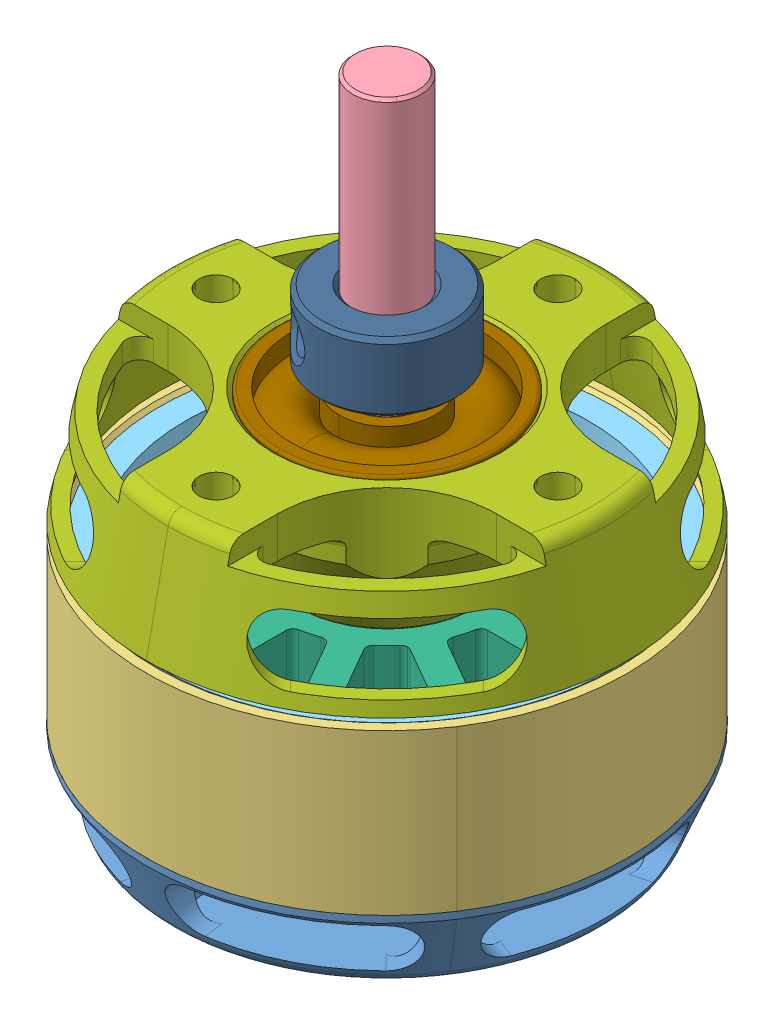
SolidWorks assembly Tempest-2808-Motor.STEP, configuration Default. Lengths in mm.
Overall size (48.72 48.7 48.72).
24 component instances, 10 part files, 0 mates.
Components (placement in the parent):
- 2808+_+++T+_.STEP-1: 2808+_+++T+_.STEP [Default] at (-20.8858 -10.9925 57.3737) x (0.837169 0 0.546944) z (0.546944 0 -0.837169) size (35.2 48.7 35.2)
  - 28-_--__+_.STEP-1: 28-_--__+_.STEP [Default] at (0.1731 5.2402 35.2) size (35.2 12.5 35.2)
  - 2808_+__.STEP-1: 2808_+__.STEP [Default] at (0.1731 -8.7598 35.2) x (-1 0 0) z (0 -1 0) size (5.3 2.55 8)
  - 2808-G+_.STEP-1: 2808-G+_.STEP [Default] at (0.1731 -8.3098 35.2) x (1 0 0) z (0 -1 0) size (35.2 35.2 11.7)
  - 2808+_+_.STEP-1: 2808+_+_.STEP [Default] at (0.1731 5.2402 35.2) x (0 1 0) z (-1 0 0) size (48.7 4.99 4.99)
  - 2808_+__.STEP-2: 2808_+__.STEP [Default] at (0.1731 -8.7598 35.2) x (-0.900969 0 -0.433884) z (0 -1 0) size (5.3 2.55 8)
  - 2808_+__.STEP-3: 2808_+__.STEP [Default] at (0.1731 -8.7598 35.2) x (-0.62349 0 -0.781831) z (0 -1 0) size (5.3 2.55 8)
  - 2808_+__.STEP-4: 2808_+__.STEP [Default] at (0.1731 -8.7598 35.2) x (-0.222521 0 -0.974928) z (0 -1 0) size (5.3 2.55 8)
  - 2808_+__.STEP-5: 2808_+__.STEP [Default] at (0.1731 -8.7598 35.2) x (0.222521 0 -0.974928) z (0 -1 0) size (5.3 2.55 8)
  - 2808_+__.STEP-6: 2808_+__.STEP [Default] at (0.1731 -8.7598 35.2) x (0.62349 0 -0.781831) z (0 -1 0) size (5.3 2.55 8)
  - 2808_+__.STEP-7: 2808_+__.STEP [Default] at (0.1731 -8.7598 35.2) x (0.900969 0 -0.433884) z (0 -1 0) size (5.3 2.55 8)
  - 2808_+__.STEP-8: 2808_+__.STEP [Default] at (0.1731 -8.7598 35.2) x (1 0 0) z (0 -1 0) size (5.3 2.55 8)
  - 2808_+__.STEP-9: 2808_+__.STEP [Default] at (0.1731 -8.7598 35.2) x (0.900969 0 0.433884) z (0 -1 0) size (5.3 2.55 8)
  - 2808_+__.STEP-10: 2808_+__.STEP [Default] at (0.1731 -8.7598 35.2) x (0.62349 0 0.781831) z (0 -1 0) size (5.3 2.55 8)
  - 2808_+__.STEP-11: 2808_+__.STEP [Default] at (0.1731 -8.7598 35.2) x (0.222521 0 0.974928) z (0 -1 0) size (5.3 2.55 8)
  - 2808_+__.STEP-12: 2808_+__.STEP [Default] at (0.1731 -8.7598 35.2) x (-0.222521 0 0.974928) z (0 -1 0) size (5.3 2.55 8)
  - 2808_+__.STEP-13: 2808_+__.STEP [Default] at (0.1731 -8.7598 35.2) x (-0.62349 0 0.781831) z (0 -1 0) size (5.3 2.55 8)
  - 2808_+__.STEP-14: 2808_+__.STEP [Default] at (0.1731 -8.7598 35.2) x (-0.900969 0 0.433884) z (0 -1 0) size (5.3 2.55 8)
  - XTO-28-_-- _+___+14__.STEP-1: XTO-28-_-- _+___+14__.STEP [Default] at (0.1731 -22.7598 35.2) x (1 0 0) z (0 0 -1) size (33.2 3.7 33.2)
- 2808__++__-+.STEP-1: 2808__++__-+.STEP [Default] at (-1.4885 -2.2327 28) size (28 8 28)
- 2808_=+_.STEP-1: 2808_=+_.STEP [Default] at (-1.4885 12.4673 28) x (0 -1 0) z (0 0 1) size (20.45 35.2 35.2)
- +__-685-ZZ.STEP-1: +__-685-ZZ.STEP [Default] at (-1.4885 -2.9827 28) x (0 -1 0) z (0 0 1) size (5 11 11)
- +__-625-ZZ.STEP-1: +__-625-ZZ.STEP [Default] at (-1.4885 7.4673 28) x (0 1 0) z (0 0 1) size (5.11 16 16)
- 5.0__+_++.STEP-1: 5.0__+_++.STEP [Default] at (-1.4885 14.0173 28) x (0.837169 0 0.546944) z (-0.546944 0 0.837169) size (10 5 10)
